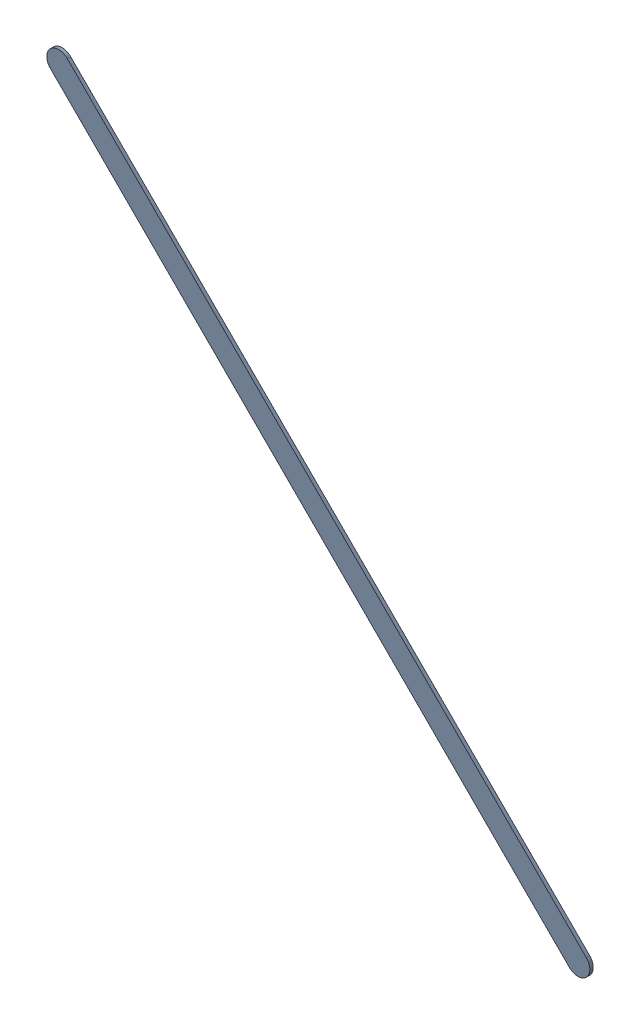
SolidWorks assembly Track (11.2mm,38mm)(16.7mm,32.5mm) on Top Layer, configuration Predeterminado. Lengths in mm.
Overall size (5.75 5.75 0.04).
2 component instances, 1 part files, 0 mates.
Components (placement in the parent):
- Track (11.2mm,38mm)(16.7mm,32.5mm) on Top Layer-1-1: Track (11.2mm,38mm)(16.7mm,32.5mm) on Top Layer-1 [Predeterminado] at (-68.317 -44.187 -0.0457) size (5.75 5.75 0.04)
  - Track (11.2mm,38mm)(16.7mm,32.5mm) on Top Layer-Part-1-1: Track (11.2mm,38mm)(16.7mm,32.5mm) on Top Layer-Part-1 [Predeterminado] at origin size (5.75 5.75 0.04)
